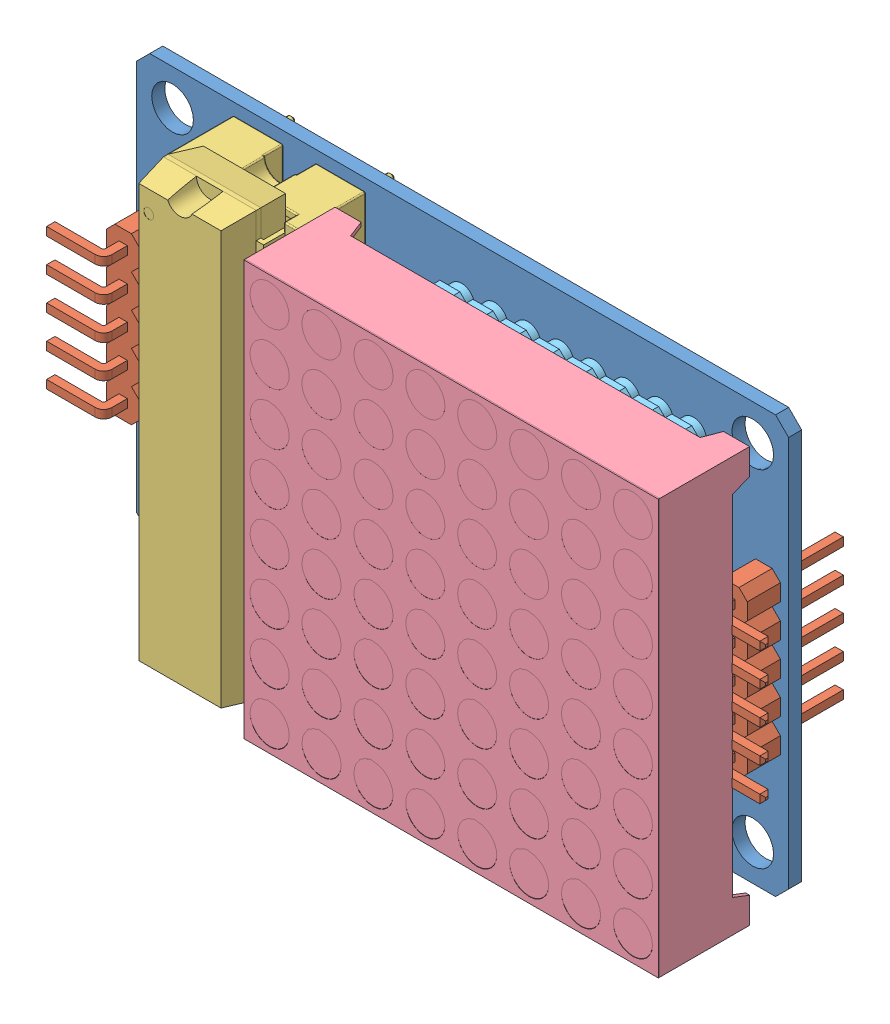
SolidWorks assembly MAX7219 8x8 LED Dot Matrix Display Module, configuration Default. Lengths in mm.
Overall size (55.14 32.51 16).
10 component instances, 8 part files, 29 mates.
Components (placement in the parent):
- PCB-1: PCB [Default] at (20.1471 25.9698 38.68) x (-1 0 0) z (0 0 -1) size (50 32 1)
- 90 5xHeader Pins-1: 90 5xHeader Pins [Default] at (-4.6529 25.5098 38.88) x (0 -1 0) z (1 0 0) size (12.7 10.36 5.54)
- 90 5xHeader Pins-2: 90 5xHeader Pins [Default] at (44.5471 25.2698 38.88) x (0 1 0) z (-1 0 0) size (12.7 10.36 5.54)
- MAX7812 with DIP-1: MAX7812 with DIP [Default] at (7.6571 25.8648 38.5143) x (0 -1 0) z (0 0 1) size (32.51 10.16 12.41)
- 1088AS-1: 1088AS [Default] at (13.3571 41.8698 48.68) x (0 -1 0) z (-1 0 0) size (31.81 10.5 31.8)
- 8x female rounded header-1: 8x female rounded header [Default] at (30.5271 13.9698 42.88) size (20.32 2.54 7.43)
- 8x female rounded header-2: 8x female rounded header [Default] at (30.5271 37.9698 42.88) size (20.32 2.54 7.43)
- C1 0.1uF-1: C1 0.1uF [Default] at (15.1471 25.0998 38.5349) x (0 1 0) z (0 0 1) size (9.4 2.5 8.73)
- R1 10K Resistor-1: R1 10K Resistor [Default] at (18.5871 20.8698 39.2601) size (8.12 2.2 5.6)
- C2-1: C2 [Default] at (22.6717 25.2698 41.596) x (0 0 -1) z (1 0 0) size (7.92 5 8.7)
Mates (geometry in assembly coordinates):
- Coincident1: coincident anti-aligned: plane of PCB-1 through (20.1471 25.9698 38.68) normal (0 0 1); plane of 90 5xHeader Pins-1 through (-3.3529 20.4098 38.68) normal (0 0 -1)
- Width3: width: cylinder of 90 5xHeader Pins-1; plane of PCB-1 through (-3.0329 30.8898 38.68) normal (1 0 0); cylinder of 90 5xHeader Pins-1 through (-3.3529 30.5698 36.2658) axis (0 0 1) radius 0.5
- Width4: width: plane of 90 5xHeader Pins-1 through (-3.6729 30.8898 38.68) normal (0 1 0); plane of PCB-1 through (-3.0329 30.2498 38.68) normal (0 -1 0); cylinder of 90 5xHeader Pins-1 through (-3.3529 30.5698 36.2658) axis (0 0 1) radius 0.5
- Width5: width: plane of 90 5xHeader Pins-1 through (-3.6729 20.0898 38.68) normal (-1 0 0); plane of PCB-1 through (-3.0329 20.7298 38.68) normal (1 0 0); cylinder of 90 5xHeader Pins-1 through (-3.3529 20.4098 36.2658) axis (0 0 1) radius 0.5
- Coincident2: coincident anti-aligned: plane of PCB-1 through (20.1471 25.9698 38.68) normal (0 0 1); plane of 90 5xHeader Pins-2 through (43.2471 30.3698 38.68) normal (0 0 -1)
- Width6: width: plane of 90 5xHeader Pins-2 through (43.5671 30.0498 38.68) normal (0 -1 0); plane of PCB-1 through (42.9271 30.6898 38.68) normal (0 1 0); cylinder of 90 5xHeader Pins-2 through (43.2471 30.3698 36.2658) axis (0 0 1) radius 0.5
- Width7: width: plane of 90 5xHeader Pins-2 through (43.5671 20.5298 38.68) normal (1 0 0); plane of PCB-1 through (42.9271 19.8898 38.68) normal (-1 0 0); cylinder of 90 5xHeader Pins-2 through (43.2471 20.2098 36.2658) axis (0 0 1) radius 0.5
- Width8: width: plane of 90 5xHeader Pins-2 through (43.5671 30.6898 38.68) normal (1 0 0); plane of PCB-1 through (42.9271 30.0498 38.68) normal (-1 0 0); cylinder of 90 5xHeader Pins-2 through (43.2471 30.3698 36.2658) axis (0 0 1) radius 0.5
- Concentric1: concentric aligned: cylinder of PCB-1 through (11.4671 39.8198 36.2658) axis (0 0 1) radius 0.5; cylinder of MAX7812 with DIP-1 through (11.4671 39.8198 38.68) axis (0 0 1) radius 0.3
- Concentric2: concentric aligned: cylinder of PCB-1 through (11.4671 11.8798 36.2658) axis (0 0 1) radius 0.5; cylinder of MAX7812 with DIP-1 through (11.4671 11.8798 38.68) axis (0 0 1) radius 0.3
- Coincident3: coincident anti-aligned: plane of PCB-1 through (20.1471 25.9698 38.68) normal (0 0 1); plane of MAX7812 with DIP-1 through (2.5771 41.0898 38.68) normal (0 0 -1)
- Concentric3: concentric aligned: cylinder of PCB-1 through (20.3671 13.9698 36.2658) axis (0 0 1) radius 0.5; cylinder of 1088AS-1 through (20.3671 13.9698 38.18) axis (0 0 1) radius 0.25
- Concentric4: concentric aligned: cylinder of PCB-1 through (38.1471 13.9698 36.2658) axis (0 0 1) radius 0.5; cylinder of 1088AS-1 through (38.1471 13.9698 38.18) axis (0 0 1) radius 0.25
- Distance1: distance = 11 mm anti-aligned: plane of 1088AS-1 through (13.3571 41.8698 48.68) normal (0 0 1); plane of PCB-1 through (20.1471 25.9698 37.68) normal (0 0 -1)
- Coincident5: coincident anti-aligned: plane of PCB-1 through (20.1471 25.9698 38.68) normal (0 0 1); plane of 8x female rounded header-1 through (20.3671 13.9698 38.68) normal (0 0 -1)
- Concentric5: concentric aligned: cylinder of PCB-1 through (20.3671 13.9698 36.2658) axis (0 0 1) radius 0.5; cylinder of 8x female rounded header-1 through (20.3671 13.9698 35.45) axis (0 0 1) radius 0.255
- Concentric6: concentric aligned: cylinder of PCB-1 through (38.1471 13.9698 36.2658) axis (0 0 1) radius 0.5; cylinder of 8x female rounded header-1 through (38.1471 13.9698 35.45) axis (0 0 1) radius 0.255
- Concentric7: concentric aligned: cylinder of PCB-1 through (38.1471 37.9698 36.2658) axis (0 0 1) radius 0.5; cylinder of 8x female rounded header-2 through (38.1471 37.9698 35.45) axis (0 0 1) radius 0.255
- Concentric8: concentric aligned: cylinder of PCB-1 through (20.3671 37.9698 36.2658) axis (0 0 1) radius 0.5; cylinder of 8x female rounded header-2 through (20.3671 37.9698 35.45) axis (0 0 1) radius 0.255
- Coincident6: coincident anti-aligned: plane of PCB-1 through (20.1471 25.9698 38.68) normal (0 0 1); plane of 8x female rounded header-2 through (33.0671 37.9698 38.68) normal (0 0 -1)
- Concentric9: concentric aligned: cylinder of PCB-1 through (15.1471 23.8298 36.2658) axis (0 0 1) radius 0.5; cylinder of C1 0.1uF-1 through (15.1471 23.8298 14.88) axis (0 0 1) radius 0.25
- Concentric10: concentric aligned: cylinder of PCB-1 through (15.1471 26.3698 36.2658) axis (0 0 1) radius 0.5; cylinder of C1 0.1uF-1 through (15.1471 26.3698 14.88) axis (0 0 1) radius 0.25
- Distance2: distance = 1.5 mm aligned: plane of C1 0.1uF-1 through (15.1471 25.0998 36.18) normal (0 0 -1); plane of PCB-1 through (20.1471 25.9698 37.68) normal (0 0 -1)
- Concentric11: concentric anti-aligned: cylinder of PCB-1 through (14.7771 20.8698 36.2658) axis (0 0 1) radius 0.5; cylinder of R1 10K Resistor-1 through (14.7771 20.8698 40.18) axis (0 0 -1) radius 0.25
- Concentric12: concentric aligned: cylinder of PCB-1 through (22.3971 20.8698 36.2658) axis (0 0 1) radius 0.5; cylinder of R1 10K Resistor-1 through (22.3971 20.8698 40.18) axis (0 0 1) radius 0.25
- Coincident9: coincident aligned: plane of C1 0.1uF-1 through (15.1471 25.0998 36.18) normal (0 0 -1); plane of R1 10K Resistor-1 through (14.7771 20.8698 36.18) normal (0 0 -1)
- Concentric14: concentric: cylinder of PCB-1 through (21.2471 26.2698 36.2658) axis (0 0 1) radius 0.5; cylinder of C2-1 through (21.2471 26.2698 41.0849) axis (0 0 -1) radius 0.225
- Concentric15: concentric: cylinder of PCB-1 through (21.2471 24.2698 36.2658) axis (0 0 1) radius 0.5; cylinder of C2-1 through (21.2471 24.2698 41.0849) axis (0 0 -1) radius 0.225
- Distance3: distance = 1.5 mm aligned: plane of C2-1 through (21.2471 26.2698 36.18) normal (0 0 -1); plane of PCB-1 through (20.1471 25.9698 37.68) normal (0 0 -1)
